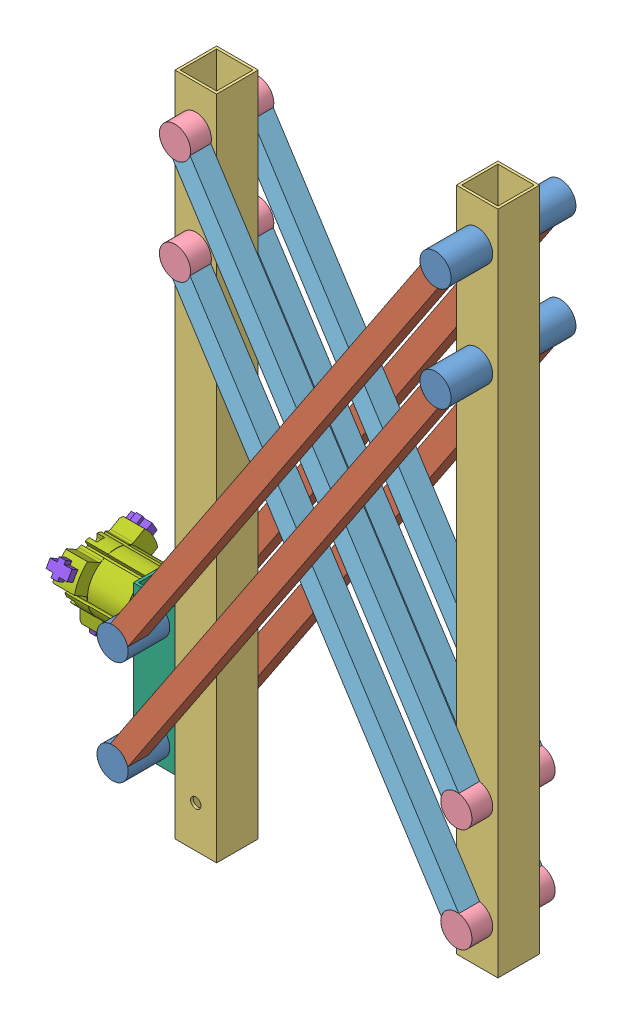
SolidWorks assembly Arm Assembly, configuration Down. Lengths in mm.
Overall size (522.52 862.88 156.64).
24 component instances, 8 part files, 47 mates.
Components (placement in the parent):
- End Long-1: End Long [Default] at (368.8196 -282.6753 -37.7204) x (0.945044 0.326943 0) z (0 0 1)
- Link Long-1: Link Long [Default] at (-14.8296 -881.6578 13.0796) x (0.554302 0.832316 0) z (0.832316 -0.554302 0)
- Link Long-2: Link Long [Default] at (-14.8296 -881.6578 -113.9204) x (0.554302 0.832316 0) z (0.832316 -0.554302 0)
- End Long-2: End Long [Default] at (-25.4 -874.6181 -37.7204) x (-0.401382 -0.915911 0) z (0 0 1)
- End Long-3: End Long [Default] at (-25.4 -747.6181 -37.7204) x (-0.425631 -0.904897 0) z (0 0 1)
- Link Long-3: Link Long [Default] at (-14.8296 -754.6578 13.0796) x (0.554302 0.832316 0) z (0.832316 -0.554302 0)
- Link Long-4: Link Long [Default] at (-14.8296 -754.6578 -113.9204) x (0.554302 0.832316 0) z (0.832316 -0.554302 0)
- End Long-4: End Long [Default] at (368.8196 -155.6753 -37.7204) x (0.945044 0.326943 0) z (0 0 1)
- Post-2: Post [Default] at (368.8196 -104.8753 -37.7204) x (0 0 -1) z (-1 0 0)
- End Short-1: End Short [Default] at (25.4 -332.7517 -37.7204) x (0.945044 0.326943 0) z (0 0 1)
- End Short-2: End Short [Default] at (368.8196 -866.8753 -37.7204) x (0.945044 0.326943 0) z (0 0 1)
- Link Short-1: Link Short [Default] at (14.7175 -339.6201 -88.5204) x (0.540818 -0.841139 0) z (-0.841139 -0.540818 0)
- Link Short-2: Link Short [Default] at (14.7175 -339.6201 -12.3204) x (0.540818 -0.841139 0) z (-0.841139 -0.540818 0)
- Link Short-3: Link Short [Default] at (14.7175 -212.6201 -12.3204) x (0.540818 -0.841139 0) z (-0.841139 -0.540818 0)
- Link Short-4: Link Short [Default] at (14.7175 -212.6201 -88.5204) x (0.540818 -0.841139 0) z (-0.841139 -0.540818 0)
- End Short-3: End Short [Default] at (368.8196 -739.8753 -37.7204) x (0.945044 0.326943 0) z (0 0 1)
- End Short-4: End Short [Default] at (25.4 -205.7517 -37.7204) x (0.945044 0.326943 0) z (0 0 1)
- Post-4: Post [Default] at (25.4 -967.7517 -37.7204) x (0 0 -1) z (1 0 0)
- Post Short-1: Post Short [Default] at (-25.4 -900.0181 -37.7204) x (0 0 -1) z (1 0 0)
- MHSL3-50D-1: MHSL3-50D [MHSL3-50D] at (-50.8 -757.2181 -37.7204) x (-1 0 0) z (0 -0.866025 0.5) size (77.5 98.66 113.92)
  - MHSL3-50D_MHSL-Body-1: MHSL3-50D_MHSL-Body [50] x (-1 0 0) z (0 0 -1) size (74.5 90.6 101.7)
  - MHSL3-50D_MHSL-Finger-1: MHSL3-50D_MHSL-Finger [50] at (61 -48 0) x (-1 0 0) z (0 0 1) size (26.2 24 20)
  - MHSL3-50D_MHSL-Finger-2: MHSL3-50D_MHSL-Finger [50] at (61 24 41.5692) x (-1 0 0) z (0 0.866025 -0.5) size (26.2 24 20)
  - MHSL3-50D_MHSL-Finger-3: MHSL3-50D_MHSL-Finger [50] at (61 24 -41.5692) x (-1 0 0) z (0 -0.866025 -0.5) size (26.2 24 20)
Mates (geometry in assembly coordinates):
- Concentric1: concentric anti-aligned: cylinder of End Long-1 through (368.8196 -282.6753 -113.9204) axis (0 0 -1) radius 19.05; cylinder of Link Long-1 through (368.8196 -282.6753 13.0796) axis (0 0 1) radius 19.05
- Coincident1: coincident aligned: plane of End Long-1 through (368.8196 -282.6753 38.4796) normal (0 0 1); plane of Link Long-1 through (379.39 -289.7149 38.4796) normal (0 0 1)
- Concentric2: concentric anti-aligned: cylinder of End Long-1 through (368.8196 -282.6753 -113.9204) axis (0 0 -1) radius 19.05; cylinder of Link Long-2 through (368.8196 -282.6753 -113.9204) axis (0 0 1) radius 19.05
- Coincident2: coincident aligned: plane of End Long-1 through (362.5913 -264.6722 -113.9204) normal (0 0 -1); plane of Link Long-2 through (379.39 -289.7149 -113.9204) normal (0 0 -1)
- Concentric3: concentric anti-aligned: cylinder of Link Long-1 through (-25.4 -874.6181 13.0796) axis (0 0 1) radius 19.05; cylinder of End Long-2 through (-25.4 -874.6181 -113.9204) axis (0 0 -1) radius 19.05
- Coincident3: coincident aligned: plane of Link Long-1 through (379.39 -289.7149 38.4796) normal (0 0 1); plane of End Long-2 through (-25.4 -874.6181 38.4796) normal (0 0 1)
- Concentric4: concentric anti-aligned: cylinder of Link Long-4 through (368.8196 -155.6753 -113.9204) axis (0 0 1) radius 19.05; cylinder of End Long-4 through (368.8196 -155.6753 -113.9204) axis (0 0 -1) radius 19.05
- Concentric5: concentric anti-aligned: cylinder of End Long-3 through (-25.4 -747.6181 -113.9204) axis (0 0 -1) radius 19.05; cylinder of Link Long-3 through (-25.4 -747.6181 13.0796) axis (0 0 1) radius 19.05
- Concentric6: concentric anti-aligned: cylinder of Link Long-3 through (368.8196 -155.6753 13.0796) axis (0 0 1) radius 19.05; cylinder of End Long-4 through (368.8196 -155.6753 -113.9204) axis (0 0 -1) radius 19.05
- Coincident4: coincident aligned: plane of End Long-3 through (-25.4 -747.6181 38.4796) normal (0 0 1); plane of Link Long-3 through (379.39 -162.7149 38.4796) normal (0 0 1)
- Coincident5: coincident aligned: plane of Link Long-4 through (379.39 -162.7149 -113.9204) normal (0 0 -1); plane of End Long-4 through (362.5913 -137.6722 -113.9204) normal (0 0 -1)
- Coincident6: coincident aligned: plane of Link Long-3 through (379.39 -162.7149 38.4796) normal (0 0 1); plane of End Long-4 through (368.8196 -155.6753 38.4796) normal (0 0 1)
- Concentric7: concentric anti-aligned: cylinder of End Long-1 through (368.8196 -282.6753 -113.9204) axis (0 0 -1) radius 6.35; circle of Post-2
- Concentric8: concentric anti-aligned: cylinder of End Long-4 through (368.8196 -155.6753 -113.9204) axis (0 0 -1) radius 6.35; circle of Post-2
- Coincident9: coincident aligned: plane of Link Long-1 through (379.39 -289.7149 38.4796) normal (0 0 1); plane of Link Long-3 through (379.39 -162.7149 38.4796) normal (0 0 1)
- Distance1: distance = 50.8 mm aligned: plane of End Long-4 through (368.8196 -155.6753 38.4796) normal (0 0 1); plane of Post-2 through (394.2196 -917.6753 -12.3204) normal (0 0 1)
- Concentric9: concentric anti-aligned: cylinder of Link Long-2 through (-25.4 -874.6181 -113.9204) axis (0 0 1) radius 19.05; cylinder of End Long-2 through (-25.4 -874.6181 -113.9204) axis (0 0 -1) radius 19.05
- Concentric10: concentric anti-aligned: cylinder of End Long-3 through (-25.4 -747.6181 -113.9204) axis (0 0 -1) radius 19.05; cylinder of Link Long-4 through (-25.4 -747.6181 -113.9204) axis (0 0 1) radius 19.05
- Concentric11: concentric anti-aligned: cylinder of End Short-2 through (368.8196 -866.8753 -88.5204) axis (0 0 -1) radius 19.05; cylinder of Link Short-2 through (368.8196 -866.8753 -12.3204) axis (0 0 1) radius 19.05
- Coincident11: coincident aligned: plane of End Short-2 through (368.8196 -866.8753 13.0796) normal (0 0 1); plane of Link Short-2 through (358.1371 -873.7437 13.0796) normal (0 0 1)
- Concentric12: concentric anti-aligned: cylinder of End Short-1 through (25.4 -332.7517 -88.5204) axis (0 0 -1) radius 19.05; cylinder of Link Short-2 through (25.4 -332.7517 -12.3204) axis (0 0 1) radius 19.05
- Coincident12: coincident aligned: plane of End Short-1 through (25.4 -332.7517 13.0796) normal (0 0 1); plane of Link Short-2 through (358.1371 -873.7437 13.0796) normal (0 0 1)
- Concentric13: concentric anti-aligned: cylinder of End Short-1 through (25.4 -332.7517 -88.5204) axis (0 0 -1) radius 19.05; cylinder of Link Short-1 through (25.4 -332.7517 -88.5204) axis (0 0 1) radius 19.05
- Coincident13: coincident aligned: plane of End Short-1 through (19.1717 -314.7486 -88.5204) normal (0 0 -1); plane of Link Short-1 through (358.1371 -873.7437 -88.5204) normal (0 0 -1)
- Concentric14: concentric anti-aligned: cylinder of End Short-2 through (368.8196 -866.8753 -88.5204) axis (0 0 -1) radius 19.05; cylinder of Link Short-1 through (368.8196 -866.8753 -88.5204) axis (0 0 1) radius 19.05
- Concentric15: concentric anti-aligned: cylinder of Link Short-3 through (25.4 -205.7517 -12.3204) axis (0 0 1) radius 19.05; cylinder of End Short-4 through (25.4 -205.7517 -88.5204) axis (0 0 -1) radius 19.05
- Concentric16: concentric anti-aligned: cylinder of Link Short-4 through (368.8196 -739.8753 -88.5204) axis (0 0 1) radius 19.05; cylinder of End Short-3 through (368.8196 -739.8753 -88.5204) axis (0 0 -1) radius 19.05
- Concentric17: concentric anti-aligned: cylinder of Link Short-4 through (25.4 -205.7517 -88.5204) axis (0 0 1) radius 19.05; cylinder of End Short-4 through (25.4 -205.7517 -88.5204) axis (0 0 -1) radius 19.05
- Concentric18: concentric anti-aligned: cylinder of Link Short-3 through (368.8196 -739.8753 -12.3204) axis (0 0 1) radius 19.05; cylinder of End Short-3 through (368.8196 -739.8753 -88.5204) axis (0 0 -1) radius 19.05
- Coincident14: coincident aligned: plane of Link Short-4 through (358.1371 -746.7437 -88.5204) normal (0 0 -1); plane of End Short-4 through (19.1717 -187.7486 -88.5204) normal (0 0 -1)
- Coincident15: coincident aligned: plane of Link Short-3 through (358.1371 -746.7437 13.0796) normal (0 0 1); plane of End Short-4 through (25.4 -205.7517 13.0796) normal (0 0 1)
- Coincident16: coincident aligned: plane of Link Short-3 through (358.1371 -746.7437 13.0796) normal (0 0 1); plane of End Short-3 through (368.8196 -739.8753 13.0796) normal (0 0 1)
- Concentric19: concentric anti-aligned: circle of Post-2; cylinder of End Short-3 through (368.8196 -739.8753 -88.5204) axis (0 0 -1) radius 6.35
- Coincident18: coincident aligned: plane of Link Short-2 through (358.1371 -873.7437 13.0796) normal (0 0 1); plane of Link Short-3 through (358.1371 -746.7437 13.0796) normal (0 0 1)
- Concentric20: concentric anti-aligned: circle of Post-2; cylinder of End Short-2 through (368.8196 -866.8753 -88.5204) axis (0 0 -1) radius 6.35
- Distance2: distance = 25.4 mm aligned: plane of End Short-3 through (368.8196 -739.8753 13.0796) normal (0 0 1); plane of Post-2 through (394.2196 -917.6753 -12.3204) normal (0 0 1)
- Concentric24: concentric anti-aligned: cylinder of End Short-4 through (25.4 -205.7517 -88.5204) axis (0 0 -1) radius 6.35; circle of Post-4
- Concentric25: concentric anti-aligned: cylinder of End Short-1 through (25.4 -332.7517 -88.5204) axis (0 0 -1) radius 6.35; circle of Post-4
- Distance5: distance = 25.4 mm aligned: plane of End Short-1 through (25.4 -332.7517 13.0796) normal (0 0 1); plane of Post-4 through (0 -154.9517 -12.3204) normal (0 0 1)
- Concentric26: concentric anti-aligned: cylinder of End Long-3 through (-25.4 -747.6181 -113.9204) axis (0 0 -1) radius 6.35; circle of Post Short-1
- Concentric27: concentric anti-aligned: cylinder of End Long-2 through (-25.4 -874.6181 -113.9204) axis (0 0 -1) radius 6.35; circle of Post Short-1
- Distance6: distance = 50.8 mm aligned: plane of Post Short-1 through (-50.8 -722.2181 -12.3204) normal (0 0 1); plane of End Long-2 through (-25.4 -874.6181 38.4796) normal (0 0 1)
- Coincident21: coincident anti-aligned: plane of Post Short-1 through (-50.8 -722.2181 -12.3204) normal (-1 0 0); plane of MHSL3-50D-1/MHSL3-50D_MHSL-Body-1 through (-50.8 -770.2181 -60.237) normal (1 0 0)
- Parallel1: parallel aligned: plane of Post Short-1 through (-50.8 -722.2181 -12.3204) normal (0 0 1); plane of MHSL3-50D-1/MHSL3-50D_MHSL-Body-1 through (-50.8 -806.6954 -21.7204) normal (0 0 1)
- Coincident25: coincident: moEndPointRef_w of Post Short-1; moEndPointRef_w of MHSL3-50D-1/MHSL3-50D_MHSL-Body-1
- Coincident26: coincident anti-aligned: plane of Post-4 through (0 -154.9517 -12.3204) normal (-1 0 0); plane of assembly through (0 0 0) normal (1 0 0)
- Coincident28: coincident anti-aligned: plane of Post-4 through (0 -154.9517 -12.3204) normal (-1 0 0); plane of Post Short-1 through (0 -722.2181 -12.3204) normal (1 0 0)
